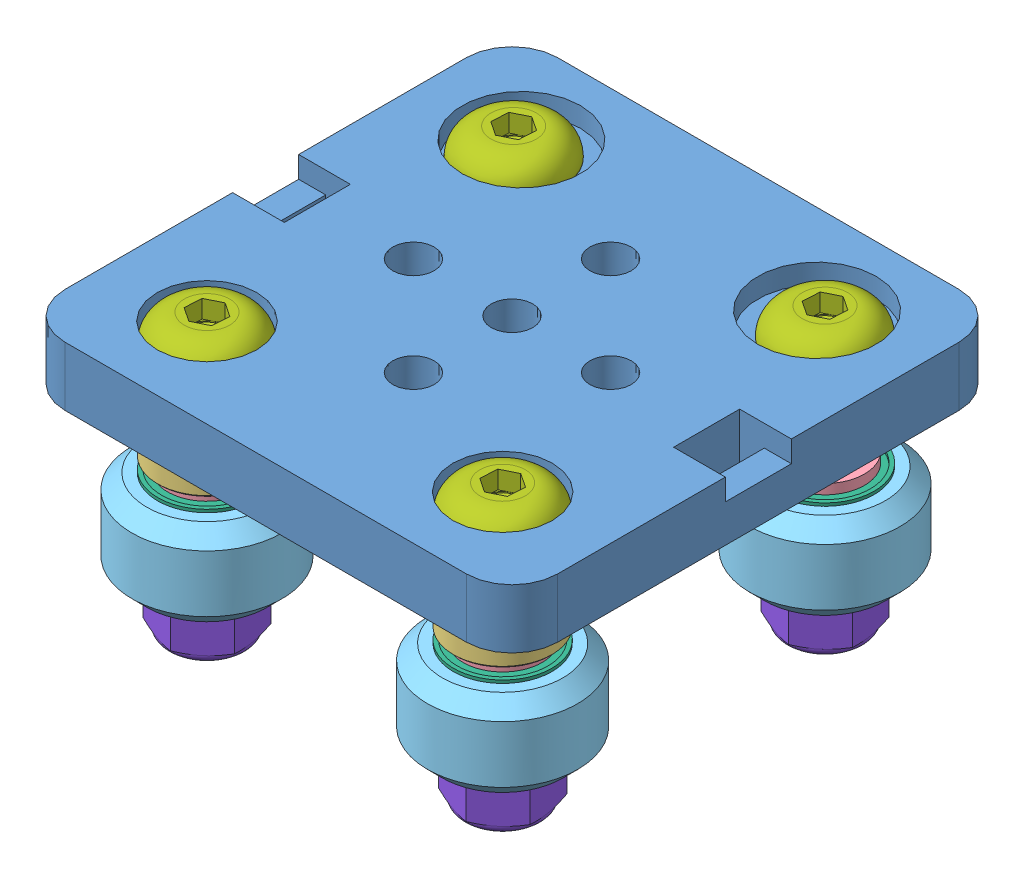
SolidWorks assembly Mini V Gantry Set, configuration По умолчанию. Lengths in mm.
Overall size (50 28.2 50).
37 component instances, 8 part files, 31 mates.
Components (placement in the parent):
- Mini V Gantry Plate-1: Mini V Gantry Plate [Default] at origin size (50 6 50)
- Mini Eccentric Spacer 6mm-1: Mini Eccentric Spacer 6mm [Default] at (15 -1 -15.95) x (0.025234 0 0.999682) z (0.999682 0 -0.025234) size (10 8.5 9.7)
- Mini Eccentric Spacer 6mm-2: Mini Eccentric Spacer 6mm [Default] at (-15 -1 -15.95) x (0.013093 0 -0.999914) z (-0.999914 0 -0.013093) size (10 8.5 9.7)
- Aluminum Spacer 6mm-1: Aluminum Spacer 6mm [Default] at (-15 -6 15.95) x (0.819475 0 -0.573115) z (0 1 0) size (10 10 6)
- Aluminum Spacer 6mm-2: Aluminum Spacer 6mm [Default] at (15 -6 15.95) x (0.874148 0 -0.485659) z (0 1 0) size (10 10 6)
- Mini V Wheel Precision Shim-1: Mini V Wheel Precision Shim [По умолчанию] at (-15 -6 15.95) x (0 -1 0) z (0.934174 0 -0.356817) size (1 8 8)
- Mini V Wheel Precision Shim-2: Mini V Wheel Precision Shim [По умолчанию] at (15 -6 15.95) x (0 -1 0) z (0.934174 0 -0.356817) size (1 8 8)
- Mini V Wheel Precision Shim-3: Mini V Wheel Precision Shim [По умолчанию] at (-15.7899 -6 -15.9603) x (0 -1 0) z (0.934174 0 -0.356817) size (1 8 8)
- Mini V Wheel Precision Shim-4: Mini V Wheel Precision Shim [По умолчанию] at (15.7897 -6 -15.9699) x (0 -1 0) z (0.934174 0 -0.356817) size (1 8 8)
- Delrin Mini V Wheel Kit-1: Delrin Mini V Wheel Kit [По умолчанию] at (15 -11.7 15.95) x (0 1 0) z (0.022117 0 -0.999755) size (9.4 15.23 15.23)
  - Delrin Mini V Wheel-1: Delrin Mini V Wheel [Default] at origin size (8.8 15.23 15.23)
  - Mini Ball Bearing 105zz 5x10x4-1: Mini Ball Bearing 105zz 5x10x4 [Default] at (2.6 0 0) size (4.2 10 10)
  - Mini Ball Bearing 105zz 5x10x4-2: Mini Ball Bearing 105zz 5x10x4 [Default] at (-2.6 0 0) size (4.2 10 10)
  - Mini V Wheel Precision Shim-2: Mini V Wheel Precision Shim [По умолчанию] at (-0.5 0 0) size (1 8 8)
- Delrin Mini V Wheel Kit-2: Delrin Mini V Wheel Kit [По умолчанию] at (15.7897 -11.7 -15.9699) x (0 1 0) z (0.017079 0 -0.999854) size (9.4 15.23 15.23)
  - Delrin Mini V Wheel-1: Delrin Mini V Wheel [Default] at origin size (8.8 15.23 15.23)
  - Mini Ball Bearing 105zz 5x10x4-1: Mini Ball Bearing 105zz 5x10x4 [Default] at (2.6 0 0) size (4.2 10 10)
  - Mini Ball Bearing 105zz 5x10x4-2: Mini Ball Bearing 105zz 5x10x4 [Default] at (-2.6 0 0) size (4.2 10 10)
  - Mini V Wheel Precision Shim-2: Mini V Wheel Precision Shim [По умолчанию] at (-0.5 0 0) size (1 8 8)
- Delrin Mini V Wheel Kit-3: Delrin Mini V Wheel Kit [По умолчанию] at (-15 -11.7 15.95) x (0 1 0) z (-0.161014 0 -0.986952) size (9.4 15.23 15.23)
  - Delrin Mini V Wheel-1: Delrin Mini V Wheel [Default] at origin size (8.8 15.23 15.23)
  - Mini Ball Bearing 105zz 5x10x4-1: Mini Ball Bearing 105zz 5x10x4 [Default] at (2.6 0 0) size (4.2 10 10)
  - Mini Ball Bearing 105zz 5x10x4-2: Mini Ball Bearing 105zz 5x10x4 [Default] at (-2.6 0 0) size (4.2 10 10)
  - Mini V Wheel Precision Shim-2: Mini V Wheel Precision Shim [По умолчанию] at (-0.5 0 0) size (1 8 8)
- Delrin Mini V Wheel Kit-4: Delrin Mini V Wheel Kit [По умолчанию] at (-15.7899 -11.7 -15.9603) x (0 1 0) z (-0.085251 0 -0.996359) size (9.4 15.23 15.23)
  - Delrin Mini V Wheel-1: Delrin Mini V Wheel [Default] at origin size (8.8 15.23 15.23)
  - Mini Ball Bearing 105zz 5x10x4-1: Mini Ball Bearing 105zz 5x10x4 [Default] at (2.6 0 0) size (4.2 10 10)
  - Mini Ball Bearing 105zz 5x10x4-2: Mini Ball Bearing 105zz 5x10x4 [Default] at (-2.6 0 0) size (4.2 10 10)
  - Mini V Wheel Precision Shim-2: Mini V Wheel Precision Shim [По умолчанию] at (-0.5 0 0) size (1 8 8)
- M5x25 ISO7380-6: M5x25 ISO7380 [По умолчанию] at (-15 6.8 15.95) x (0 -1 0) z (0.998021 0 0.062885) size (27.8 10 10)
- M5x25 ISO7380-7: M5x25 ISO7380 [По умолчанию] at (15 6.8 15.95) x (0 -1 0) z (0.998021 0 0.062885) size (27.8 10 10)
- M5x25 ISO7380-8: M5x25 ISO7380 [По умолчанию] at (15.7897 6.8 -15.9699) x (0 -1 0) z (0.998021 0 0.062885) size (27.8 10 10)
- M5x25 ISO7380-9: M5x25 ISO7380 [По умолчанию] at (-15.7899 6.8 -15.9603) x (0 -1 0) z (0.998021 0 0.062885) size (27.8 10 10)
- Nylon Insert Lock Nut M5-3: Nylon Insert Lock Nut M5 [Default] at (-15.7899 -16.4 -15.9603) x (0.646541 0 0.762879) z (0.762879 0 -0.646541) size (8 5 9.24)
- Nylon Insert Lock Nut M5-4: Nylon Insert Lock Nut M5 [Default] at (15.7897 -16.4 -15.9699) x (0.646541 0 0.762879) z (0.762879 0 -0.646541) size (8 5 9.24)
- Nylon Insert Lock Nut M5-5: Nylon Insert Lock Nut M5 [Default] at (-15 -16.4 15.95) x (0.646541 0 0.762879) z (0.762879 0 -0.646541) size (8 5 9.24)
- Nylon Insert Lock Nut M5-6: Nylon Insert Lock Nut M5 [Default] at (15 -16.4 15.95) x (0.646541 0 0.762879) z (0.762879 0 -0.646541) size (8 5 9.24)
Mates (geometry in assembly coordinates):
- Концентричный1: concentric anti-aligned: circle of Mini V Gantry Plate-1; circle of Aluminum Spacer 6mm-2
- Совпадение1: coincident anti-aligned: plane of Mini V Gantry Plate-1 through (-20.365 0 -20.365) normal (0 -1 0); plane of Aluminum Spacer 6mm-2 through (15 0 15.95) normal (0 1 0)
- Концентричный2: concentric anti-aligned: circle of Mini V Gantry Plate-1; circle of Aluminum Spacer 6mm-1
- Совпадение2: coincident anti-aligned: plane of Mini V Gantry Plate-1 through (-20.365 0 -20.365) normal (0 -1 0); plane of Aluminum Spacer 6mm-1 through (-15 0 15.95) normal (0 1 0)
- Концентричный3: concentric aligned: circle of Mini V Gantry Plate-1; circle of Mini Eccentric Spacer 6mm-2
- Совпадение3: coincident aligned: circle of Mini V Gantry Plate-1; plane of Mini Eccentric Spacer 6mm-2 through (-15 0 -15.95) normal (0 1 0)
- Совпадение4: coincident anti-aligned: plane of Mini V Gantry Plate-1 through (-20.365 0 -20.365) normal (0 -1 0); plane of Mini Eccentric Spacer 6mm-1 through (15 0 -15.95) normal (0 1 0)
- Концентричный4: concentric aligned: circle of Mini V Gantry Plate-1; circle of Mini Eccentric Spacer 6mm-1
- Концентричный5: concentric anti-aligned: circle of Aluminum Spacer 6mm-1; circle of Mini V Wheel Precision Shim-1
- Совпадение5: coincident anti-aligned: plane of Aluminum Spacer 6mm-1 through (-15 -6 15.95) normal (0 -1 0); plane of Mini V Wheel Precision Shim-1 through (-15 -6 15.95) normal (0 1 0)
- Концентричный6: concentric anti-aligned: circle of Aluminum Spacer 6mm-2; circle of Mini V Wheel Precision Shim-2
- Совпадение6: coincident anti-aligned: plane of Aluminum Spacer 6mm-2 through (15 -6 15.95) normal (0 -1 0); plane of Mini V Wheel Precision Shim-2 through (15 -6 15.95) normal (0 1 0)
- Совпадение7: coincident aligned: circle of Mini Eccentric Spacer 6mm-2; circle of Mini V Wheel Precision Shim-3
- Концентричный7: concentric aligned: circle of Mini Eccentric Spacer 6mm-1; circle of Mini V Wheel Precision Shim-4
- Совпадение9: coincident anti-aligned: plane of Mini Eccentric Spacer 6mm-1 through (15 -6 -15.95) normal (0 -1 0); plane of Mini V Wheel Precision Shim-4 through (15.7897 -6 -15.9699) normal (0 1 0)
- Совпадение10: coincident anti-aligned: circle of Mini V Wheel Precision Shim-3; circle of Delrin Mini V Wheel Kit-4/Mini Ball Bearing 105zz 5x10x4-1
- Совпадение11: coincident anti-aligned: circle of Mini V Wheel Precision Shim-1; circle of Delrin Mini V Wheel Kit-3/Mini Ball Bearing 105zz 5x10x4-1
- Совпадение12: coincident anti-aligned: circle of Mini V Wheel Precision Shim-2; circle of Delrin Mini V Wheel Kit-1/Mini Ball Bearing 105zz 5x10x4-1
- Совпадение13: coincident anti-aligned: circle of Mini V Wheel Precision Shim-4; circle of Delrin Mini V Wheel Kit-2/Mini Ball Bearing 105zz 5x10x4-1
- Концентричный8: concentric anti-aligned: cylinder of Mini V Gantry Plate-1 through (15 6 15.95) axis (0 -1 0) radius 2.55; cylinder of M5x25 ISO7380-7 through (15 -21 15.95) axis (0 1 0) radius 2.5
- Концентричный9: concentric anti-aligned: cylinder of Mini V Gantry Plate-1 through (-15 6 15.95) axis (0 -1 0) radius 2.55; cylinder of M5x25 ISO7380-6 through (-15 -21 15.95) axis (0 1 0) radius 2.5
- Концентричный10: concentric anti-aligned: cylinder of Mini Eccentric Spacer 6mm-2 through (-15.7899 2.5 -15.9603) axis (0 -1 0) radius 2.5; cylinder of M5x25 ISO7380-9 through (-15.7899 -21 -15.9603) axis (0 1 0) radius 2.5
- Концентричный11: concentric anti-aligned: cylinder of Mini Eccentric Spacer 6mm-1 through (15.7897 2.5 -15.9699) axis (0 -1 0) radius 2.5; cylinder of M5x25 ISO7380-8 through (15.7897 -21 -15.9699) axis (0 1 0) radius 2.5
- Совпадение14: coincident aligned: plane of Mini V Gantry Plate-1 through (15 4 -15.95) normal (0 1 0); circle of M5x25 ISO7380-8
- Совпадение15: coincident anti-aligned: plane of Mini V Gantry Plate-1 through (15 4 15.95) normal (0 1 0); plane of M5x25 ISO7380-7 through (15.3144 4 10.9599) normal (0 -1 0)
- Совпадение16: coincident anti-aligned: plane of Mini V Gantry Plate-1 through (-15 4 -15.95) normal (0 1 0); plane of M5x25 ISO7380-9 through (-15.4755 4 -20.9504) normal (0 -1 0)
- Совпадение17: coincident anti-aligned: plane of Mini V Gantry Plate-1 through (-15 4 15.95) normal (0 1 0); plane of M5x25 ISO7380-6 through (-14.6856 4 10.9599) normal (0 -1 0)
- Совпадение19: coincident aligned: circle of Delrin Mini V Wheel Kit-3/Mini Ball Bearing 105zz 5x10x4-2; circle of Nylon Insert Lock Nut M5-5
- Совпадение20: coincident aligned: circle of Delrin Mini V Wheel Kit-1/Mini Ball Bearing 105zz 5x10x4-2; circle of Nylon Insert Lock Nut M5-6
- Совпадение21: coincident aligned: circle of Delrin Mini V Wheel Kit-4/Mini Ball Bearing 105zz 5x10x4-2; circle of Nylon Insert Lock Nut M5-3
- Совпадение22: coincident aligned: circle of Delrin Mini V Wheel Kit-2/Mini Ball Bearing 105zz 5x10x4-2; circle of Nylon Insert Lock Nut M5-4
